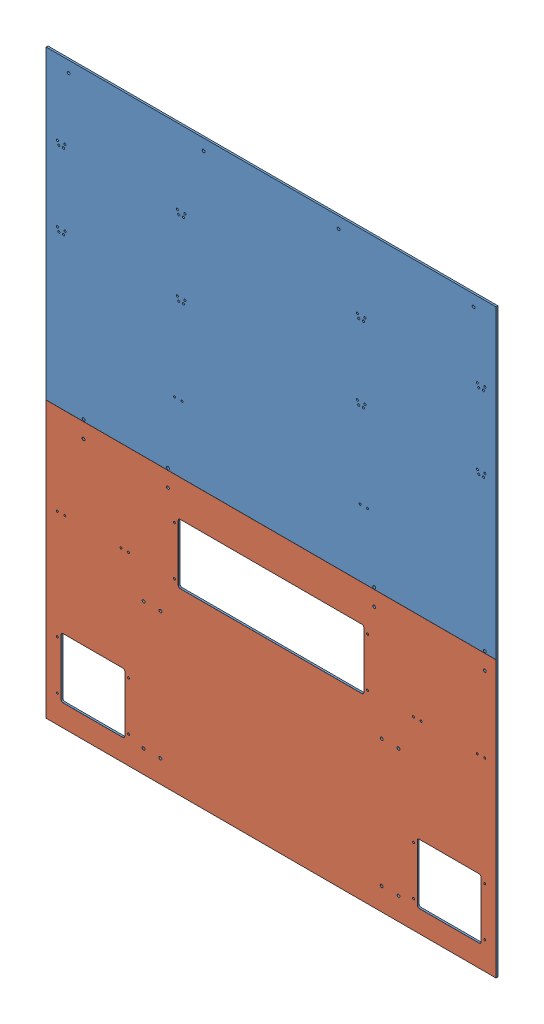
SolidWorks assembly GE-20220, configuration GE-20220-Blue. Lengths in mm.
Overall size (1524 1968.5 6.6).
2 component instances, 2 part files, 6 mates.
Components (placement in the parent):
- GE-20202-1: GE-20202 [Default] at (0 984.25 0) size (1524 1968.5 6.35)
- GE-20220-Vinyl-1: GE-20220-Vinyl [GE-20220-Blue-Vinyl] at (0 984.25 0.254) size (1524 933.45 0.25)
Mates (geometry in assembly coordinates):
- Coincident1: coincident anti-aligned: plane of GE-20202-1 through (0 984.25 0) normal (0 0 -1)
- Coincident2: coincident anti-aligned: plane of GE-20202-1 through (-762 0 6.35) normal (0 -1 0)
- Symmetric1: symmetric aligned: plane of GE-20202-1 through (-762 0 6.35) normal (-1 0 0); plane of GE-20202-1 through (762 0 6.35) normal (1 0 0)
- Coincident3: coincident anti-aligned: plane of GE-20202-1 through (0 984.25 6.35) normal (0 0 1); plane of GE-20220-Vinyl-1 through (-762 0 6.35) normal (0 0 -1)
- Coincident4: coincident aligned: plane of GE-20202-1 through (-762 0 6.35) normal (0 -1 0); plane of GE-20220-Vinyl-1 through (-762 0 6.604) normal (0 -1 0)
- Coincident5: coincident aligned: plane of GE-20202-1 through (-762 0 6.35) normal (-1 0 0); plane of GE-20220-Vinyl-1 through (-762 0 6.604) normal (-1 0 0)
